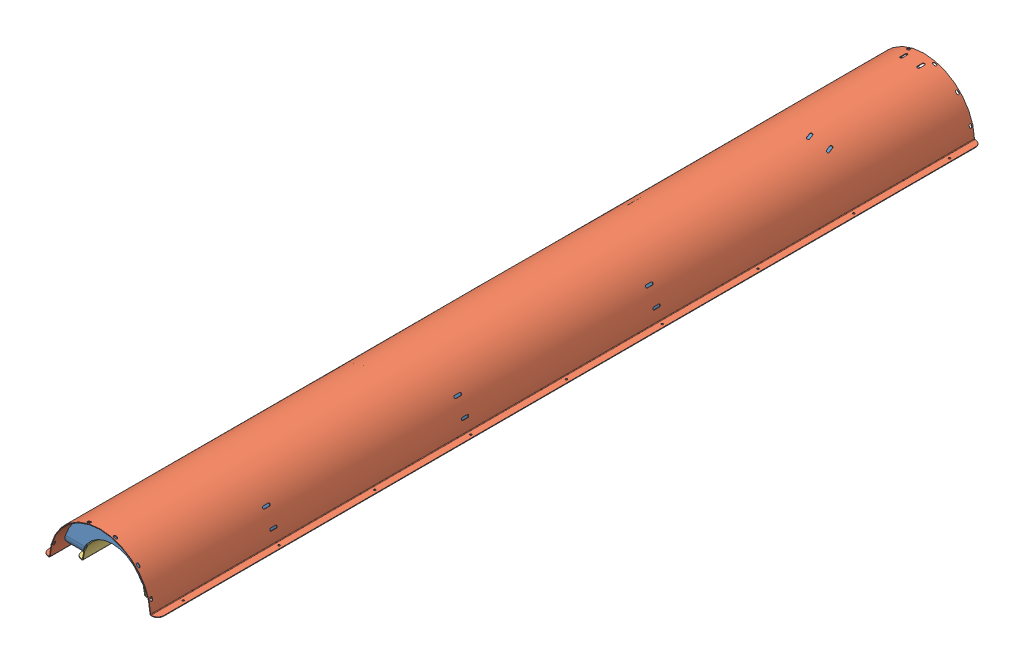
SolidWorks assembly Assem1, configuration Default. Lengths in mm.
Overall size (149.98 64.75 1071).
3 component instances, 3 part files, 4 mates.
Components (placement in the parent):
- Modified BJ heater blanket solid cyl-1: Modified BJ heater blanket solid cyl [Default] at (464.5683 519.2741 749.0541) size (128.68 59.34 1039)
- BJ outer cover-1: BJ outer cover [Default] at (464.5683 519.2741 749.0541) size (149.98 64.75 1071)
- BJ heater support-1: BJ heater support [Default] at (464.5683 519.2741 749.0541) size (99.97 40 1035)
Mates (geometry in assembly coordinates):
- Concentric1: concentric: cylinder of Modified BJ heater blanket solid cyl-1 through (464.5683 519.2741 1268.5541) axis (0 0 -1) radius 64.34; cylinder of BJ outer cover-1 through (464.5683 519.2741 1268.5541) axis (0 0 -1) radius 65
- Distance1: distance = 16 mm aligned: plane of Modified BJ heater blanket solid cyl-1 through (464.5683 519.2741 1268.5541) normal (0 0 1); plane of BJ outer cover-1 through (531.0193 521.0521 1284.5541) normal (0 0 1)
- Concentric2: concentric: cylinder of Modified BJ heater blanket solid cyl-1 through (464.5683 519.2741 1268.5541) axis (0 0 -1) radius 41.06; cylinder of BJ heater support-1 through (464.5683 519.2741 1264.5541) axis (0 0 -1) radius 41.016
- Distance3: distance = 2 mm aligned: plane of Modified BJ heater blanket solid cyl-1 through (464.5683 519.2741 229.5541) normal (0 0 -1); plane of BJ heater support-1 through (422.9076 522.0427 231.5541) normal (0 0 -1)
